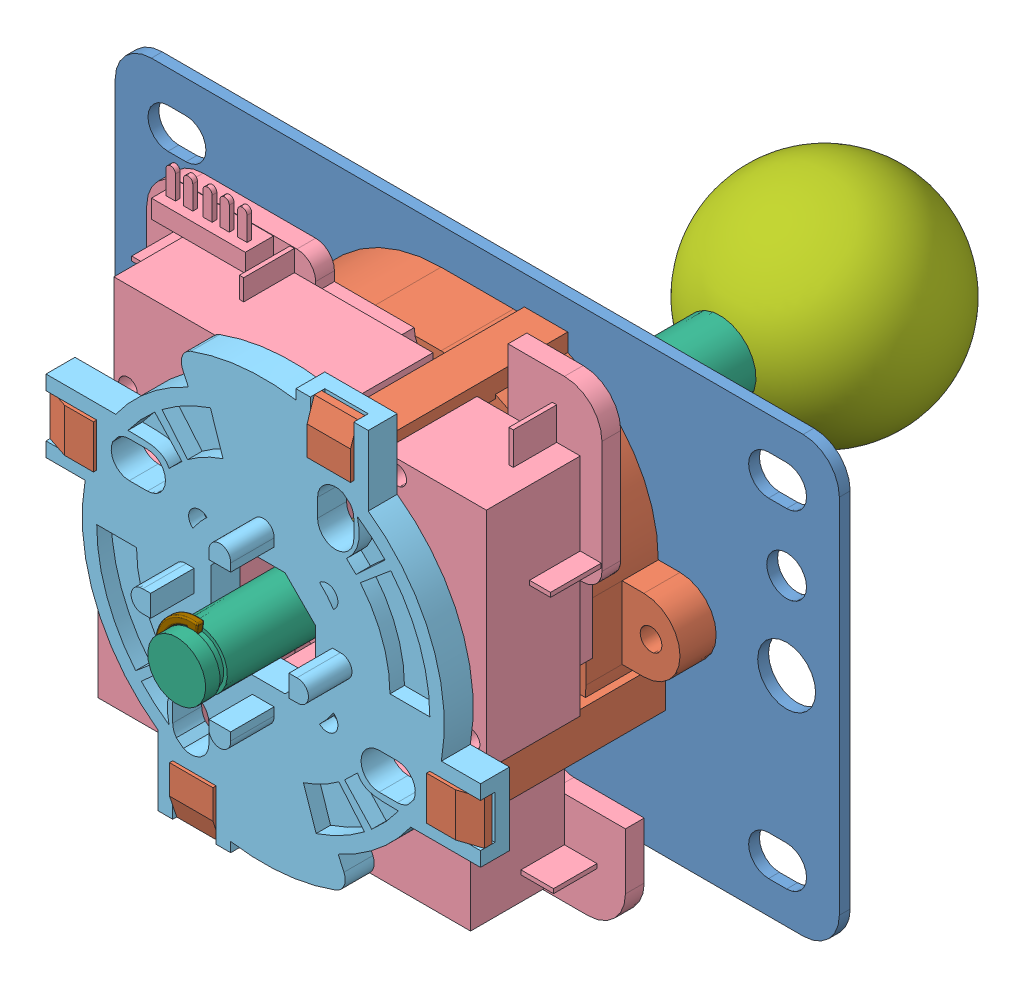
SolidWorks assembly Joystick Sanwa -Mod JLF-TP-8YT-W 1, configuration Predeterminado. Lengths in mm.
Overall size (100 66.68 104.46).
9 component instances, 9 part files, 7 mates.
Components (placement in the parent):
- SANWA_JOYSTICK_3-1: SANWA_JOYSTICK_3 [Predeterminado] at origin size (100 60 1.5)
- SSANWA_JOYSTICK_6-1: SSANWA_JOYSTICK_6 [Predeterminado] at origin size (66 60 30)
- SANWA_JOYSTICK_2-1: SANWA_JOYSTICK_2 [Predeterminado] x (1 0 0) z (0 1 0) size (39.99 20.68 39.98)
- SANWA_JOYSTICK_5-1: SANWA_JOYSTICK_5 [Predeterminado] at (0 0 12.592) x (1 0 0) z (0 0 -1) size (66.1 66.68 17.11)
- GT-Y-1: GT-Y [Predeterminado] at (0 0 27.552) size (60 60 10)
- SANWA_JOYSTICK_0-1: SANWA_JOYSTICK_0 [Predeterminado] at (0 0 7.5029) x (0.996812 -0.079782 0) z (0.079782 0.996812 0) size (10 85 10)
- BALL-1: BALL [Predeterminado] at (0 0 -47.9539) x (0.999996 -0.002826 0) z (0.002826 0.999996 0) size (30 30 30)
- DUSTER-1: DUSTER [Predeterminado] at (0 0 -6.2) x (-1 0 0) z (0 0 1) size (40 40 0.5)
- E-1: E [Predeterminado] at (0 0 39.0029) x (0.999996 -0.002826 0) z (0.002826 0.999996 0) size (5.88 1.1 10)
Mates (geometry in assembly coordinates):
- Concéntrica2: concentric aligned: cylinder of SANWA_JOYSTICK_2-1 through (0 0 -0.5) axis (0 0 1) radius 5; cylinder of SANWA_JOYSTICK_0-1 through (0 0 7.5029) axis (0 0 1) radius 4
- Concéntrica3: concentric anti-aligned: cylinder of SANWA_JOYSTICK_0-1 through (0 0 7.5029) axis (0 0 1) radius 3.5; cylinder of E-1 through (0 0 39.5029) axis (0 0 -1) radius 3.5
- Coincidente1: coincident anti-aligned: plane of SANWA_JOYSTICK_0-1 through (0 0 39.5029) normal (0 0 -1); plane of E-1 through (0 0 39.5029) normal (0 0 1)
- Concéntrica4: concentric anti-aligned: cylinder of SANWA_JOYSTICK_0-1 through (0 0 7.5029) axis (0 0 1) radius 4; cylinder of BALL-1 through (0 0 -47.9539) axis (0 0 -1) radius 4
- Coincidente2: coincident aligned: plane of SANWA_JOYSTICK_0-1 through (0 0 -33.4971) normal (0 0 -1); circle of BALL-1
- Concéntrica5: concentric aligned: cylinder of SANWA_JOYSTICK_0-1 through (0 0 7.5029) axis (0 0 1) radius 5; cylinder of DUSTER-1 through (0 0 -6) axis (0 0 1) radius 5
- Distancia1: distance = 4.2 mm anti-aligned: plane of DUSTER-1 through (0 0 -5.7) normal (0 0 1); plane of SANWA_JOYSTICK_3-1 through (0 0 -1.5) normal (0 0 -1)
